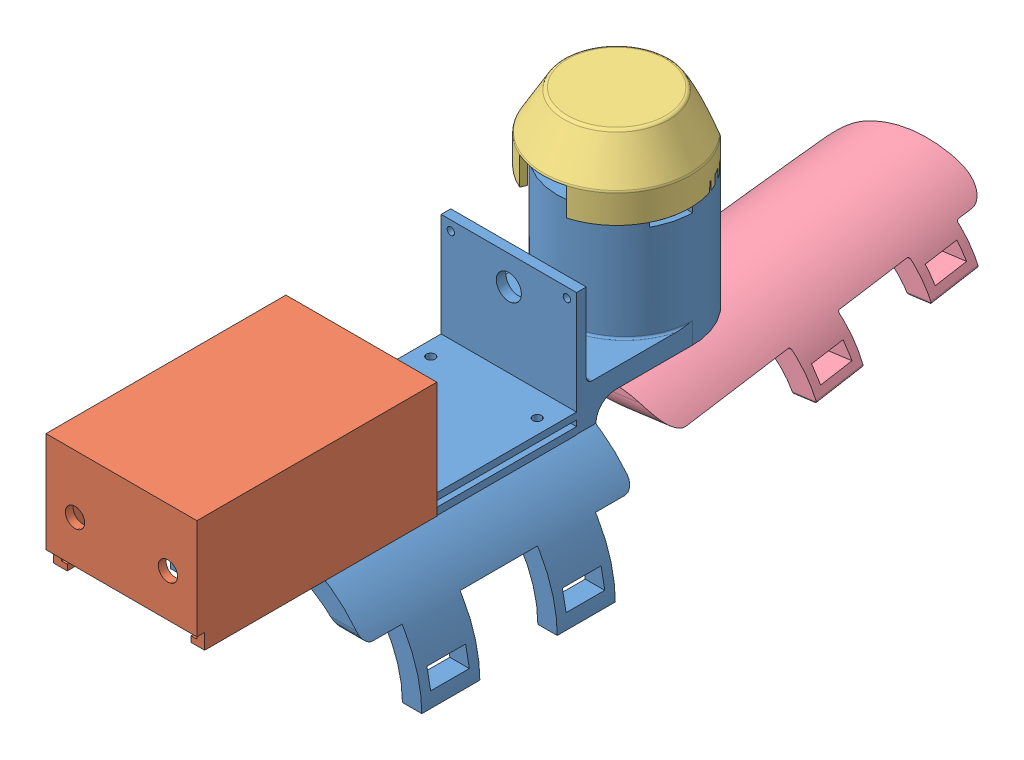
SolidWorks assembly V1 assemblage complet (avec coupleur et moteur), configuration Défaut. Lengths in mm.
Overall size (137.37 162.46 439.53).
6 component instances, 6 part files, 9 mates.
Components (placement in the parent):
- V1.3 differente haut du bras-2: V1.3 differente haut du bras [Défaut] at (-64.4299 -86.1449 197.5001) x (0 -1 0) z (0 0 1) size (132.2 130 217)
- V1 capuchon electronique-2: V1 capuchon electronique [Défaut] at (-103.4299 32.3551 283.7189) x (1 0 0) z (0 -1 0) size (78 124 60)
- capuchon moteur-3: capuchon moteur [Défaut] at (-67.0121 41.32 149.2085) x (0.997776 0 0.06666) z (-0.06666 0 0.997776) size (76 35 76)
- V1 avant bras-1: V1 avant bras [Défaut] at (-57.8908 -88.1449 173.33) x (0.988388 0 -0.151953) z (0.151953 0 0.988388) size (98.18 39.15 200)
- 37d-gearmotor-100-131-150-encoder.step-1: 37d-gearmotor-100-131-150-encoder.step [Défaut] at (-47.1743 8.7801 137.5376) x (-0.866025 0 0.5) z (0 -1 0) size (36.88 41.23 94.6)
- pololu-universal-aluminum-mounting-hub-for-6mm-shaft-m3-holes-1: pololu-universal-aluminum-mounting-hub-for-6mm-shaft-m3-holes [Défaut] at (-60.9299 -30.6449 153.5623) x (-0.475417 0 -0.879761) z (0 1 0) size (25.4 25.4 9.2)
Mates (geometry in assembly coordinates):
- Coïncidente3: coincident anti-aligned: plane of V1.3 differente haut du bras-2 through (-32.4299 -24.6449 197.4999) normal (1 0 0); plane of V1 capuchon electronique-2 through (-32.4299 -27.6449 403.7189) normal (-1 0 0)
- Coïncidente4: coincident anti-aligned: plane of V1.3 differente haut du bras-2 through (-99.4299 -24.6449 197.4999) normal (0 -1 0); plane of V1 capuchon electronique-2 through (-96.4299 -24.6449 403.7189) normal (0 1 0)
- Coaxiale3: concentric aligned: cylinder of V1.3 differente haut du bras-2 through (-64.4299 46.0551 147.5001) axis (0 -1 0) radius 19; cylinder of 37d-gearmotor-100-131-150-encoder.step-1 through (-64.4299 15.3551 147.5001) axis (0 -1 0) radius 18.4
- Coïncidente5: coincident anti-aligned: plane of V1.3 differente haut du bras-2 through (-64.4299 -11.1449 147.5001) normal (0 1 0); plane of 37d-gearmotor-100-131-150-encoder.step-1 through (-64.4299 -11.1449 147.5001) normal (0 -1 0)
- Coaxiale5: concentric anti-aligned: cylinder of V1.3 differente haut du bras-2 through (-51.0065 -31.1449 155.2501) axis (0 1 0) radius 1.9; cylinder of 37d-gearmotor-100-131-150-encoder.step-1 through (-51.0065 -8.2949 155.2501) axis (0 -1 0) radius 1.25
- Coaxiale6: concentric aligned: cylinder of 37d-gearmotor-100-131-150-encoder.step-1 through (-60.9299 -33.1449 153.5622) axis (0 1 0) radius 3; cylinder of pololu-universal-aluminum-mounting-hub-for-6mm-shaft-m3-holes-1 through (-60.9299 -33.1449 153.5622) axis (0 1 0) radius 3
- Coaxiale8: concentric anti-aligned: circle of V1 avant bras-1; cylinder of pololu-universal-aluminum-mounting-hub-for-6mm-shaft-m3-holes-1 through (-60.9299 -28.1449 153.5622) axis (0 -1 0) radius 12.7
- Coïncidente6: coincident anti-aligned: plane of V1 avant bras-1 through (-60.9299 -33.1449 153.5622) normal (0 1 0); plane of pololu-universal-aluminum-mounting-hub-for-6mm-shaft-m3-holes-1 through (-60.9299 -33.1449 153.5622) normal (0 -1 0)
- Coïncidente7: coincident anti-aligned: plane of V1 avant bras-1 through (-60.9299 -33.1449 153.5622) normal (0 1 0); plane of 37d-gearmotor-100-131-150-encoder.step-1 through (-60.9299 -33.1449 153.5622) normal (0 -1 0)
